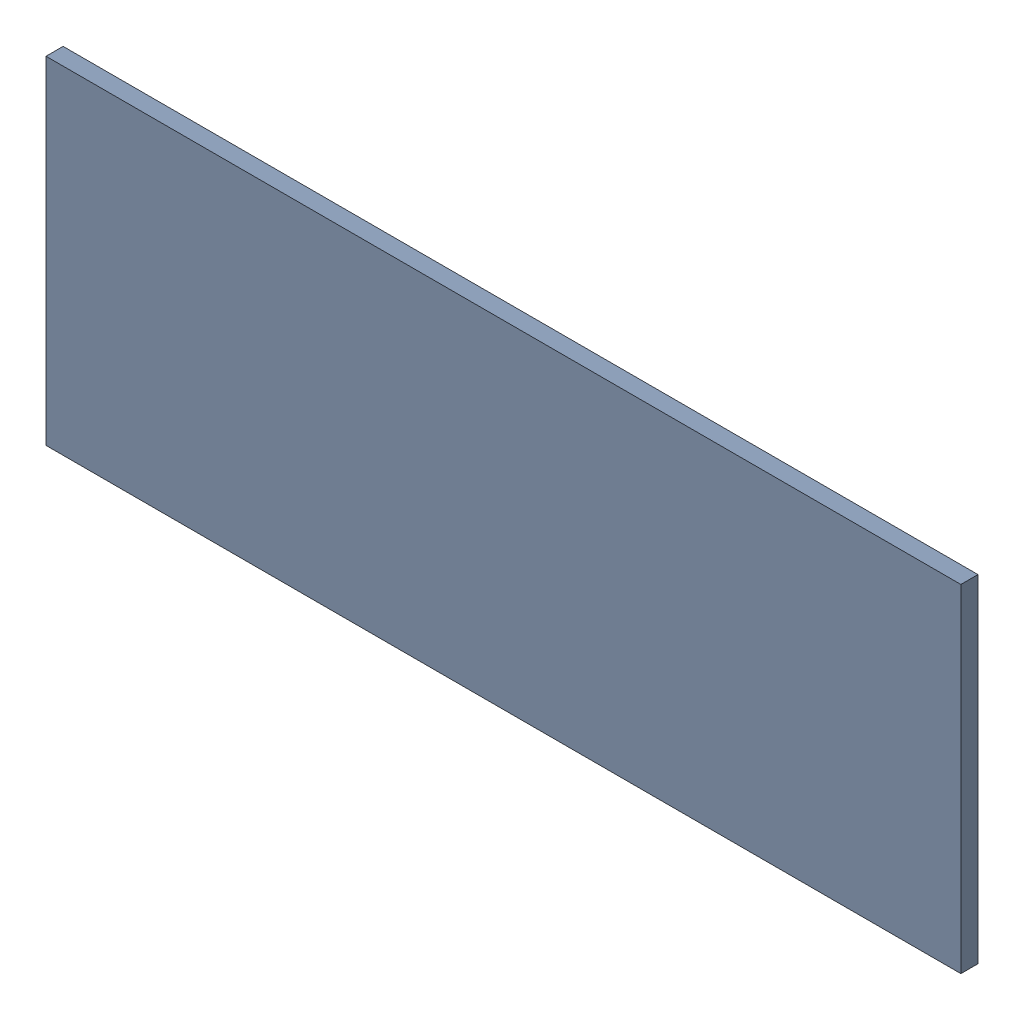
SolidWorks assembly Pad RAK4600-33(29.2mm,26.25mm) on Top Layer, configuration Predeterminado. Lengths in mm.
Overall size (1.9 0.7 0.04).
2 component instances, 1 part files, 0 mates.
Components (placement in the parent):
- Pad RAK4600-33(29.2mm,26.25mm) on Top Layer-1-1: Pad RAK4600-33(29.2mm,26.25mm) on Top Layer-1 [Predeterminado] at (-68.317 -44.187 -0.0457) size (1.9 0.7 0.04)
  - Pad RAK4600-33(29.2mm,26.25mm) on Top Layer-Part-1-1: Pad RAK4600-33(29.2mm,26.25mm) on Top Layer-Part-1 [Predeterminado] at origin size (1.9 0.7 0.04)
